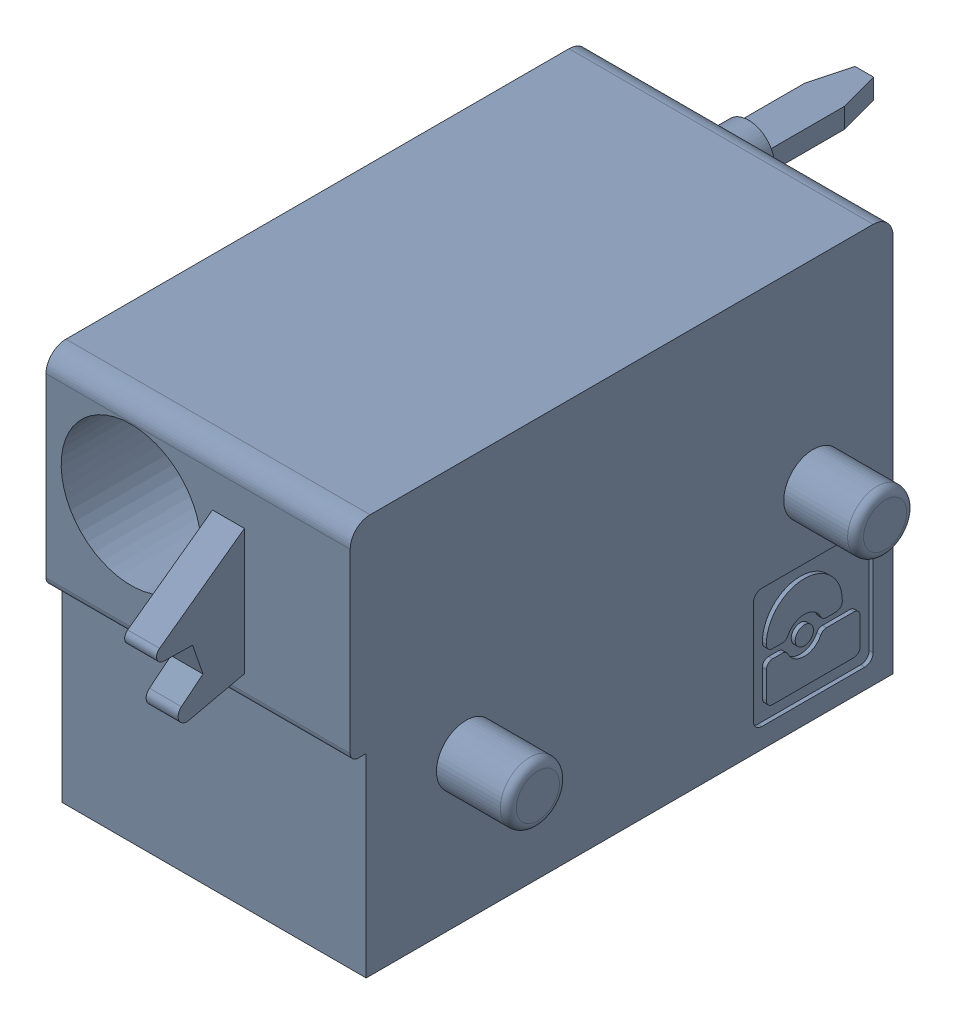
SolidWorks assembly J55, configuration Default. Lengths in mm.
Overall size (9.42 10 19.2).
2 component instances, 1 part files, 0 mates.
Components (placement in the parent):
- 1790377-1: 1790377 [Default] at (167.0051 -7.6199 0) x (0 1 0) z (1 0 0) size (10 19.2 9.42)
  - ffkdsa-v2-7.62-1: ffkdsa-v2-7.62 [Default] at (-23.7414 -38.158 -5.08) x (0 -1 0) z (0 0 1) size (19.2 10 9.42)
